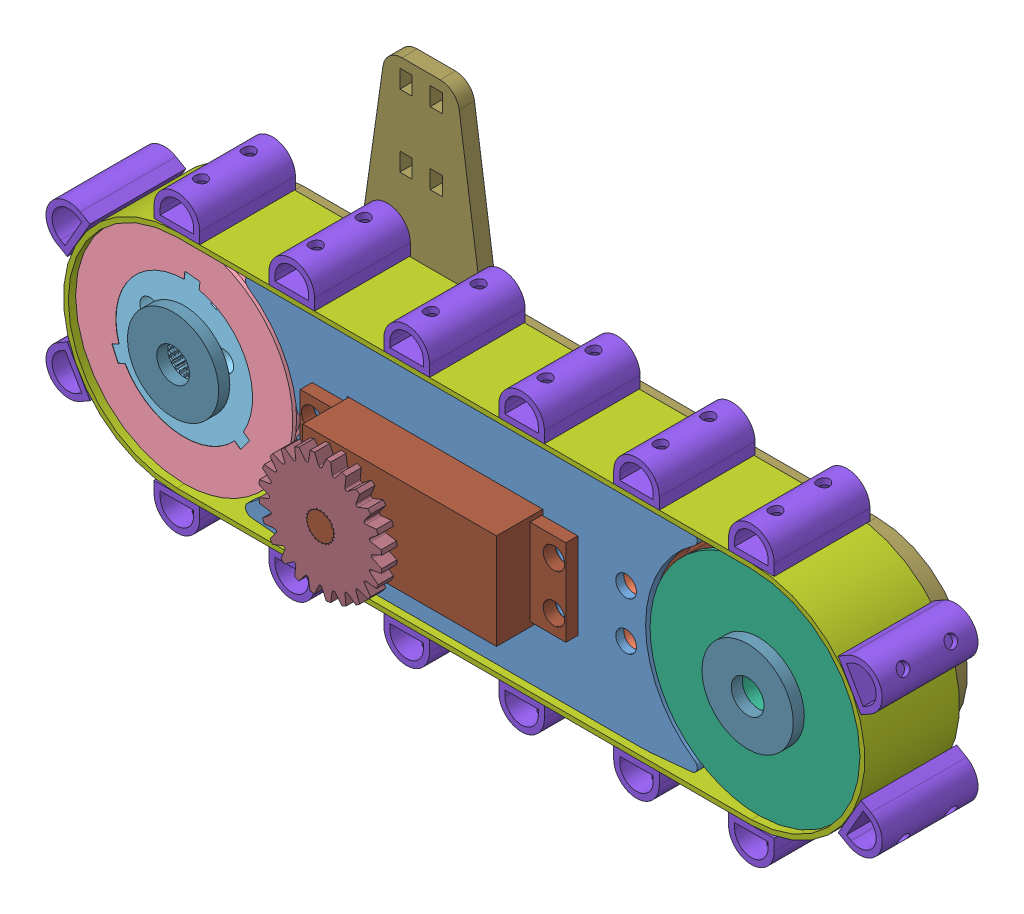
SolidWorks assembly DriveTread Assembly_R, configuration Default. Lengths in mm.
Overall size (178.18 86.48 42.8).
82 component instances, 14 part files, 27 mates.
Components (placement in the parent):
- tread runner-1: tread runner [Default] at (113.4402 41.5963 -20.788) x (-1 0 0) z (0 0 1) size (94.4 45.38 1.65)
- drive spacer_mid-1: drive spacer_mid [Default] at (14.0238 -0.101 -11.644) size (83.18 38.02 14.99)
- tread runner-2: tread runner [Default] at (113.4402 41.5963 -4.151) x (-1 0 0) z (0 0 1) size (94.4 45.38 1.65)
- drive spacer_out-1: drive spacer_out [Default] at (19.9176 6.2078 -23.9884) size (78.33 25.4 3.2)
- DriveWheel-4: DriveWheel [Default] at (-9.3084 -9.9334 -48.2482) x (0.993984 -0.109528 0) z (0 0 1) size (45.38 45.43 18.29)
  - Custom Axle Drive_LEGO UWheel_6x3-1: Custom Axle Drive_LEGO UWheel_6x3 [Default] at (6.0935 29.6872 36.6042) size (45.38 45.43 18.29)
  - WheelPlates w-Custom Axle-1: WheelPlates w-Custom Axle [Default] at (6.0935 29.6872 42.497) x (-1 0 0) z (0 0 1) size (28.95 30.08 3.2)
  - WheelPlates w-Custom Axle-2: WheelPlates w-Custom Axle [Default] at (6.0935 29.6872 27.511) x (-1 0 0) z (0 0 1) size (28.95 30.08 3.2)
- Custom Axle Float_LEGO UWheel_6x-5: Custom Axle Float_LEGO UWheel_6x [Default] at (120.015 18.9078 -11.644) x (0.969727 -0.244192 0) z (0 0 1) size (45.38 45.38 18.29)
- tread-2: tread [Default] at (0 -3.7808 -10.882) size (178.18 61.66 20)
  - tread_base-1: tread_base [Default] at origin size (167.39 47.38 19.81)
  - D-Lug_Terrain-1: D-Lug_Terrain [Default] at (0 48.7584 -10.094) size (9.53 7.14 20)
  - D-Lug_Terrain-2: D-Lug_Terrain [Default] at (-22.5771 35.7234 -10.094) x (0.5 0.866025 0) z (0 0 1) size (9.53 7.14 20)
  - D-Lug_Terrain-3: D-Lug_Terrain [Default] at (-22.5771 9.6536 -10.094) x (-0.5 0.866025 0) z (0 0 1) size (9.53 7.14 20)
  - D-Lug_Terrain-4: D-Lug_Terrain [Default] at (0 -3.3813 -10.094) x (-1 0 0) z (0 0 1) size (9.53 7.14 20)
  - D-Lug_Terrain-6: D-Lug_Terrain [Default] at (24.003 48.7584 -10.094) size (9.53 7.14 20)
  - D-Lug_Terrain-7: D-Lug_Terrain [Default] at (48.006 48.7584 -10.094) size (9.53 7.14 20)
  - D-Lug_Terrain-8: D-Lug_Terrain [Default] at (72.009 48.7584 -10.094) size (9.53 7.14 20)
  - D-Lug_Terrain-9: D-Lug_Terrain [Default] at (96.012 48.7584 -10.094) size (9.53 7.14 20)
  - D-Lug_Terrain-10: D-Lug_Terrain [Default] at (120.015 48.7584 -10.094) size (9.53 7.14 20)
  - D-Lug_Terrain-11: D-Lug_Terrain [Default] at (24.003 -3.3813 -10.094) x (-1 0 0) z (0 0 1) size (9.53 7.14 20)
  - D-Lug_Terrain-12: D-Lug_Terrain [Default] at (48.006 -3.3813 -10.094) x (-1 0 0) z (0 0 1) size (9.53 7.14 20)
  - D-Lug_Terrain-13: D-Lug_Terrain [Default] at (72.009 -3.3813 -10.094) x (-1 0 0) z (0 0 1) size (9.53 7.14 20)
  - D-Lug_Terrain-14: D-Lug_Terrain [Default] at (96.012 -3.3813 -10.094) x (-1 0 0) z (0 0 1) size (9.53 7.14 20)
  - D-Lug_Terrain-15: D-Lug_Terrain [Default] at (142.5921 35.7234 -10.094) x (0.5 -0.866025 0) z (0 0 1) size (9.53 7.14 20)
  - D-Lug_Terrain-16: D-Lug_Terrain [Default] at (142.5921 9.6536 -10.094) x (-0.5 -0.866025 0) z (0 0 1) size (9.53 7.14 20)
  - D-Lug_Terrain-17: D-Lug_Terrain [Default] at (120.015 -3.3813 -10.094) x (-1 0 0) z (0 0 1) size (9.53 7.14 20)
  - DriveLug_x-1: DriveLug_x [Default] at (-2.7045 0 0) size (5.84 6.24 14.92)
    - Drive Lug_x-1: Drive Lug_x [Default] at origin size (5.41 3.2 14.92)
    - 97334A104_NYLON SOCKET HEAD CAP SCREW-1: 97334A104_NYLON SOCKET HEAD CAP SCREW [97334A104] at (2.7045 0.0254 0) x (0.302379 0 0.953188) z (0 -1 0) size (4.65 4.65 6.24)
  - DriveLug_x-2: DriveLug_x [Default] at (-21.0011 13.6864 0) x (0.5 -0.866025 0) z (0 0 1) size (5.84 6.24 14.92)
    - Drive Lug_x-1: Drive Lug_x [Default] at origin size (5.41 3.2 14.92)
    - 97334A104_NYLON SOCKET HEAD CAP SCREW-1: 97334A104_NYLON SOCKET HEAD CAP SCREW [97334A104] at (2.7045 0.0254 0) x (0.302379 0 0.953188) z (0 -1 0) size (4.65 4.65 6.24)
  - DriveLug_x-3: DriveLug_x [Default] at (-18.2966 36.375 0) x (-0.5 -0.866025 0) z (0 0 1) size (5.84 6.24 14.92)
    - Drive Lug_x-1: Drive Lug_x [Default] at origin size (5.41 3.2 14.92)
    - 97334A104_NYLON SOCKET HEAD CAP SCREW-1: 97334A104_NYLON SOCKET HEAD CAP SCREW [97334A104] at (2.7045 0.0254 0) x (0.302379 0 0.953188) z (0 -1 0) size (4.65 4.65 6.24)
  - DriveLug_x-4: DriveLug_x [Default] at (2.7045 45.3771 0) x (-1 0 0) z (0 0 1) size (5.84 6.24 14.92)
    - Drive Lug_x-1: Drive Lug_x [Default] at origin size (5.41 3.2 14.92)
    - 97334A104_NYLON SOCKET HEAD CAP SCREW-1: 97334A104_NYLON SOCKET HEAD CAP SCREW [97334A104] at (2.7045 0.0254 0) x (0.302379 0 0.953188) z (0 -1 0) size (4.65 4.65 6.24)
  - DriveLug_x-5: DriveLug_x [Default] at (21.2985 0 0) size (5.84 6.24 14.92)
    - Drive Lug_x-1: Drive Lug_x [Default] at origin size (5.41 3.2 14.92)
    - 97334A104_NYLON SOCKET HEAD CAP SCREW-1: 97334A104_NYLON SOCKET HEAD CAP SCREW [97334A104] at (2.7045 0.0254 0) x (0.302379 0 0.953188) z (0 -1 0) size (4.65 4.65 6.24)
  - DriveLug_x-6: DriveLug_x [Default] at (45.3015 0 0) size (5.84 6.24 14.92)
    - Drive Lug_x-1: Drive Lug_x [Default] at origin size (5.41 3.2 14.92)
    - 97334A104_NYLON SOCKET HEAD CAP SCREW-1: 97334A104_NYLON SOCKET HEAD CAP SCREW [97334A104] at (2.7045 0.0254 0) x (0.302379 0 0.953188) z (0 -1 0) size (4.65 4.65 6.24)
  - DriveLug_x-7: DriveLug_x [Default] at (69.3045 0 0) size (5.84 6.24 14.92)
    - Drive Lug_x-1: Drive Lug_x [Default] at origin size (5.41 3.2 14.92)
    - 97334A104_NYLON SOCKET HEAD CAP SCREW-1: 97334A104_NYLON SOCKET HEAD CAP SCREW [97334A104] at (2.7045 0.0254 0) x (0.302379 0 0.953188) z (0 -1 0) size (4.65 4.65 6.24)
  - DriveLug_x-8: DriveLug_x [Default] at (93.3075 0 0) size (5.84 6.24 14.92)
    - Drive Lug_x-1: Drive Lug_x [Default] at origin size (5.41 3.2 14.92)
    - 97334A104_NYLON SOCKET HEAD CAP SCREW-1: 97334A104_NYLON SOCKET HEAD CAP SCREW [97334A104] at (2.7045 0.0254 0) x (0.302379 0 0.953188) z (0 -1 0) size (4.65 4.65 6.24)
  - DriveLug_x-9: DriveLug_x [Default] at (117.3105 0 0) size (5.84 6.24 14.92)
    - Drive Lug_x-1: Drive Lug_x [Default] at origin size (5.41 3.2 14.92)
    - 97334A104_NYLON SOCKET HEAD CAP SCREW-1: 97334A104_NYLON SOCKET HEAD CAP SCREW [97334A104] at (2.7045 0.0254 0) x (0.302379 0 0.953188) z (0 -1 0) size (4.65 4.65 6.24)
  - DriveLug_x-10: DriveLug_x [Default] at (138.3116 9.0021 0) x (0.5 0.866025 0) z (0 0 1) size (5.84 6.24 14.92)
    - Drive Lug_x-1: Drive Lug_x [Default] at origin size (5.41 3.2 14.92)
    - 97334A104_NYLON SOCKET HEAD CAP SCREW-1: 97334A104_NYLON SOCKET HEAD CAP SCREW [97334A104] at (2.7045 0.0254 0) x (0.302379 0 0.953188) z (0 -1 0) size (4.65 4.65 6.24)
  - DriveLug_x-11: DriveLug_x [Default] at (141.0161 31.6907 0) x (-0.5 0.866025 0) z (0 0 1) size (5.84 6.24 14.92)
    - Drive Lug_x-1: Drive Lug_x [Default] at origin size (5.41 3.2 14.92)
    - 97334A104_NYLON SOCKET HEAD CAP SCREW-1: 97334A104_NYLON SOCKET HEAD CAP SCREW [97334A104] at (2.7045 0.0254 0) x (0.302379 0 0.953188) z (0 -1 0) size (4.65 4.65 6.24)
  - DriveLug_x-12: DriveLug_x [Default] at (122.7195 45.3771 0) x (-1 0 0) z (0 0 1) size (5.84 6.24 14.92)
    - Drive Lug_x-1: Drive Lug_x [Default] at origin size (5.41 3.2 14.92)
    - 97334A104_NYLON SOCKET HEAD CAP SCREW-1: 97334A104_NYLON SOCKET HEAD CAP SCREW [97334A104] at (2.7045 0.0254 0) x (0.302379 0 0.953188) z (0 -1 0) size (4.65 4.65 6.24)
  - DriveLug_x-13: DriveLug_x [Default] at (26.7075 45.3771 0) x (-1 0 0) z (0 0 1) size (5.84 6.24 14.92)
    - Drive Lug_x-1: Drive Lug_x [Default] at origin size (5.41 3.2 14.92)
    - 97334A104_NYLON SOCKET HEAD CAP SCREW-1: 97334A104_NYLON SOCKET HEAD CAP SCREW [97334A104] at (2.7045 0.0254 0) x (0.302379 0 0.953188) z (0 -1 0) size (4.65 4.65 6.24)
  - DriveLug_x-14: DriveLug_x [Default] at (50.7105 45.3771 0) x (-1 0 0) z (0 0 1) size (5.84 6.24 14.92)
    - Drive Lug_x-1: Drive Lug_x [Default] at origin size (5.41 3.2 14.92)
    - 97334A104_NYLON SOCKET HEAD CAP SCREW-1: 97334A104_NYLON SOCKET HEAD CAP SCREW [97334A104] at (2.7045 0.0254 0) x (0.302379 0 0.953188) z (0 -1 0) size (4.65 4.65 6.24)
  - DriveLug_x-15: DriveLug_x [Default] at (74.7135 45.3771 0) x (-1 0 0) z (0 0 1) size (5.84 6.24 14.92)
    - Drive Lug_x-1: Drive Lug_x [Default] at origin size (5.41 3.2 14.92)
    - 97334A104_NYLON SOCKET HEAD CAP SCREW-1: 97334A104_NYLON SOCKET HEAD CAP SCREW [97334A104] at (2.7045 0.0254 0) x (0.302379 0 0.953188) z (0 -1 0) size (4.65 4.65 6.24)
  - DriveLug_x-16: DriveLug_x [Default] at (98.7165 45.3771 0) x (-1 0 0) z (0 0 1) size (5.84 6.24 14.92)
    - Drive Lug_x-1: Drive Lug_x [Default] at origin size (5.41 3.2 14.92)
    - 97334A104_NYLON SOCKET HEAD CAP SCREW-1: 97334A104_NYLON SOCKET HEAD CAP SCREW [97334A104] at (2.7045 0.0254 0) x (0.302379 0 0.953188) z (0 -1 0) size (4.65 4.65 6.24)
- Servo_ContRotation-4: Servo_ContRotation [Default] at (74.747 8.9078 -2.5) x (0 1 0) z (0 0 1) size (20 55.5 42.8)
- drive plate_out-2: drive plate_out [Default] at (0 0 -27.1888) size (157.83 74.55 3.2)
- 24T Gear _Futaba Spline-2: 24T Gear _Futaba Spline [Default] at (44.647 18.9078 10.5017) size (25.67 25.67 3.2)
- wheelspacer-1: wheelspacer [Default] at (120.015 18.9078 -23.0994) size (19.05 19.05 2.31)
- wheelspacer-2: wheelspacer [Default] at (0 18.9078 -23.0994) size (19.05 19.05 2.31)
- wheelspacer-3: wheelspacer [Default] at (120.015 18.9078 -2.5) size (19.05 19.05 2.31)
- wheelspacer-4: wheelspacer [Default] at (0 18.9078 -2.5) size (19.05 19.05 2.31)
Mates (geometry in assembly coordinates):
- Coincident6: coincident: plane of tread runner-1 through (120.015 18.9078 -19.137) normal (0 0 1); plane of drive spacer_mid-1 through (0 18.9078 -19.137) normal (0 0 -1)
- Coincident8: coincident: plane of drive spacer_mid-1 through (0 18.9078 -4.151) normal (0 0 1); plane of tread runner-2 through (120.015 18.9078 -4.151) normal (0 0 -1)
- Concentric15: concentric: cylinder of drive spacer_mid-1 through (29.247 13.9078 -25.2436) axis (0 0 1) radius 2.159; cylinder of tread runner-2 through (29.247 13.9078 -10.2576) axis (0 0 1) radius 2.159
- Concentric17: concentric: cylinder of tread runner-2 through (29.247 13.9078 -10.2576) axis (0 0 1) radius 2.159; cylinder of drive spacer_out-1 through (29.247 13.9078 -30.095) axis (0 0 1) radius 2.159
- Concentric18: concentric: cylinder of tread runner-2 through (79.747 23.9078 -10.2576) axis (0 0 1) radius 2.159; cylinder of drive spacer_out-1 through (79.747 23.9078 -30.095) axis (0 0 1) radius 2.159
- Concentric39: concentric: cylinder of tread runner-1 through (79.747 13.9078 -26.8946) axis (0 0 1) radius 2.159; cylinder of drive spacer_mid-1 through (79.747 13.9078 -25.2436) axis (0 0 1) radius 2.159
- Concentric40: concentric: cylinder of tread runner-1 through (29.247 23.9078 -26.8946) axis (0 0 1) radius 2.159; cylinder of drive spacer_mid-1 through (29.247 23.9078 -25.2436) axis (0 0 1) radius 2.159
- Concentric62: concentric: cylinder of drive spacer_mid-1 through (92.3222 23.9078 -25.2436) axis (0 0 1) radius 2.159; cylinder of tread runner-2 through (92.3222 23.9078 -10.2576) axis (0 0 1) radius 2.159
- Coincident34: coincident: plane of Custom Axle Float_LEGO UWheel_6x-5 through (120.015 18.9078 -20.788) normal (0 0 -1); plane of tread-2/tread_base-1 through (120.015 18.9078 -20.788) normal (0 0 -1)
- Coincident39: coincident: plane of tread runner-1 through (120.015 18.9078 -20.788) normal (0 0 -1); plane of drive spacer_out-1 through (0 18.9078 -20.788) normal (0 0 1)
- Coincident40: coincident: plane of tread runner-2 through (120.015 18.9078 -2.5) normal (0 0 1); plane of Servo_ContRotation-4 through (74.747 8.9078 -2.5) normal (0 0 -1)
- Coincident46: coincident: plane of drive spacer_out-1 through (0 18.9078 -23.9884) normal (0 0 -1); plane of drive plate_out-2 through (0 18.9078 -23.9884) normal (0 0 1)
- Concentric73: concentric: cylinder of drive spacer_out-1 through (29.247 23.9078 -30.095) axis (0 0 1) radius 2.159; cylinder of drive plate_out-2 through (29.247 23.9078 -23.9884) axis (0 0 -1) radius 2.159
- Coincident53: coincident: plane of Servo_ContRotation-4 through (44.647 18.9078 13.7021) normal (0 0 1); plane of 24T Gear _Futaba Spline-2 through (44.647 18.9078 13.7021) normal (0 0 1)
- Concentric84: concentric: cylinder of Servo_ContRotation-4 through (44.647 18.9078 13.7021) axis (0 0 -1) radius 2.794; circle of 24T Gear _Futaba Spline-2
- Coincident56: coincident: plane of DriveWheel-4/Custom Axle Drive_LEGO UWheel_6x3-1 through (0 18.9078 -20.788) normal (0 0 -1); plane of Custom Axle Float_LEGO UWheel_6x-5 through (120.015 18.9078 -20.788) normal (0 0 -1)
- Coincident58: coincident: plane of tread runner-2 through (120.015 18.9078 -2.5) normal (0 0 1); plane of Custom Axle Float_LEGO UWheel_6x-5 through (120.015 18.9078 -2.5) normal (0 0 1)
- Concentric88: concentric: cylinder of DriveWheel-4/Custom Axle Drive_LEGO UWheel_6x3-1 through (0 18.9078 -15.454) axis (0 0 1) radius 15.9245; cylinder of tread-2/tread_base-1 through (0 18.9078 -0.976) axis (0 0 -1) radius 22.6885
- Concentric89: concentric: cylinder of Custom Axle Float_LEGO UWheel_6x-5 through (120.015 18.9078 -14.6943) axis (0 0 1) radius 15.9245; cylinder of tread-2/tread_base-1 through (120.015 18.9078 -0.976) axis (0 0 -1) radius 22.6885
- Coincident59: coincident: plane of Custom Axle Float_LEGO UWheel_6x-5 through (120.015 18.9078 -20.788) normal (0 0 -1); plane of wheelspacer-1 through (120.015 18.9078 -20.788) normal (0 0 1)
- Concentric90: concentric: cylinder of Custom Axle Float_LEGO UWheel_6x-5 through (120.015 18.9078 -2.5) axis (0 0 -1) radius 3.429; cylinder of wheelspacer-1 through (120.015 18.9078 -20.788) axis (0 0 -1) radius 3.429
- Coincident60: coincident: plane of DriveWheel-4/Custom Axle Drive_LEGO UWheel_6x3-1 through (0 18.9078 -20.788) normal (0 0 -1); plane of wheelspacer-2 through (0 18.9078 -20.788) normal (0 0 1)
- Concentric91: concentric: cylinder of drive plate_out-2 through (0 18.9078 -23.9884) axis (0 0 -1) radius 2.54; cylinder of wheelspacer-2 through (0 18.9078 -20.788) axis (0 0 -1) radius 9.525
- Coincident61: coincident: plane of Custom Axle Float_LEGO UWheel_6x-5 through (120.015 18.9078 -2.5) normal (0 0 1); plane of wheelspacer-3 through (120.015 18.9078 -2.5) normal (0 0 -1)
- Concentric92: concentric: cylinder of Custom Axle Float_LEGO UWheel_6x-5 through (120.015 18.9078 -2.5) axis (0 0 -1) radius 3.429; cylinder of wheelspacer-3 through (120.015 18.9078 -0.1886) axis (0 0 -1) radius 3.429
- Coincident62: coincident: plane of DriveWheel-4/Custom Axle Drive_LEGO UWheel_6x3-1 through (0 18.9078 -2.5) normal (0 0 1); plane of wheelspacer-4 through (0 18.9078 -2.5) normal (0 0 -1)
- Concentric93: concentric: cylinder of drive plate_out-2 through (0 18.9078 -23.9884) axis (0 0 -1) radius 2.54; cylinder of wheelspacer-4 through (0 18.9078 -0.1886) axis (0 0 -1) radius 3.429
